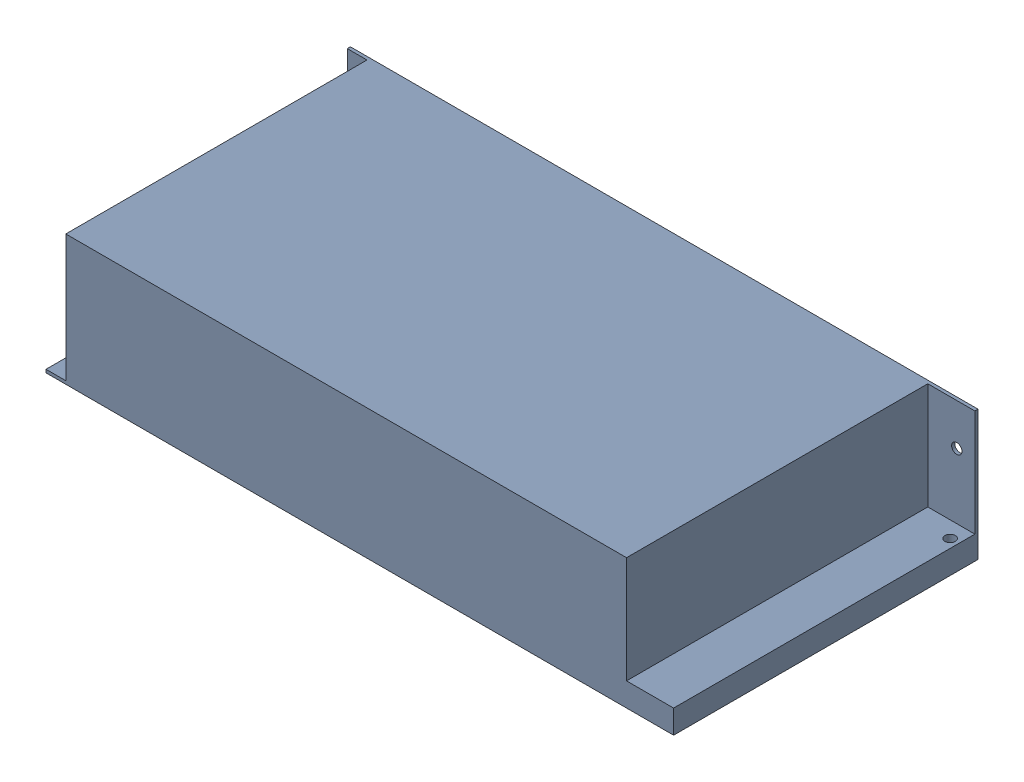
SolidWorks assembly Final1Final1PSU_assembly, configuration Default. Lengths in mm.
Overall size (200 41.5 97).
2 component instances, 2 part files, 0 mates.
Components (placement in the parent):
- Final1Final1power supply-1: Final1Final1power supply [Default] at (67.1364 125.4873 143.1383) size (200 41.5 97)
- part3^master_psu_assembly-1: part3^master_psu_assembly [Default] at origin (suppressed, hidden, virtual)
